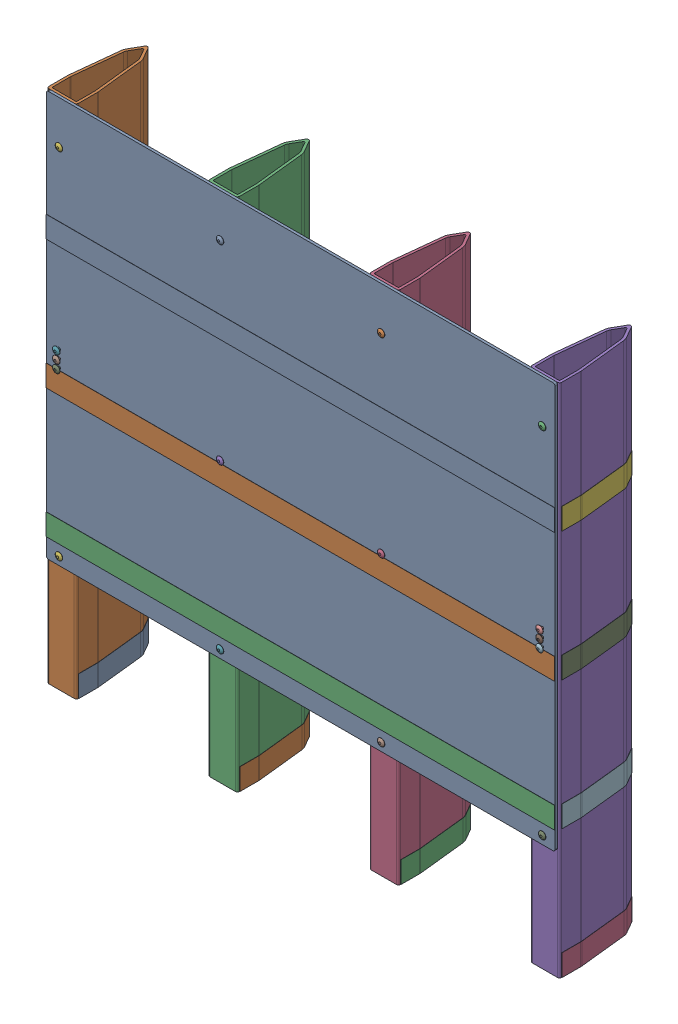
SolidWorks assembly FIELD_RelicRecovery_Crytobox C2_Cryptobox only_2, configuration Default. Lengths in mm.
Overall size (606.93 609.6 109.77).
40 component instances, 5 part files, 0 mates.
Components (placement in the parent):
- FIELD_RelicRecovery_Back Plate-1: FIELD_RelicRecovery_Back Plate [Default] at (0 317.5 -5.54) size (601.35 479.43 3)
- FIELD_RelicRecovery_Crytobox EX Rim-Triangle-1: FIELD_RelicRecovery_Crytobox EX Rim-Triangle [Default] at (-285.75 12.7 -5.54) size (34.92 609.6 101.59)
- FIELD_RelicRecovery_Crytobox EX Rim-Triangle-2: FIELD_RelicRecovery_Crytobox EX Rim-Triangle [Default] at (-95.25 12.7 -5.54) size (34.92 609.6 101.59)
- FIELD_RelicRecovery_Crytobox EX Rim-Triangle-3: FIELD_RelicRecovery_Crytobox EX Rim-Triangle [Default] at (95.25 12.7 -5.54) size (34.92 609.6 101.59)
- FIELD_RelicRecovery_Crytobox EX Rim-Triangle-4: FIELD_RelicRecovery_Crytobox EX Rim-Triangle [Default] at (285.75 12.7 -5.54) size (34.92 609.6 101.59)
- FIELD_RelicRecovery_0125 x 0500 Rivet-1: FIELD_RelicRecovery_0125 x 0500 Rivet [Default] at (-285.75 571.5 -12.065) x (1 0 0) z (0 -1 0) size (8.64 11.27 8.64)
- FIELD_RelicRecovery_0125 x 0500 Rivet-2: FIELD_RelicRecovery_0125 x 0500 Rivet [Default] at (-285.75 364.7758 -8.89) x (1 0 0) z (0 -1 0) size (8.64 11.27 8.64)
- FIELD_RelicRecovery_0125 x 0500 Rivet-3: FIELD_RelicRecovery_0125 x 0500 Rivet [Default] at (-285.75 355.2507 -8.89) x (1 0 0) z (0 -1 0) size (8.64 11.27 8.64)
- FIELD_RelicRecovery_0125 x 0500 Rivet-4: FIELD_RelicRecovery_0125 x 0500 Rivet [Default] at (-285.75 345.7258 -8.89) x (1 0 0) z (0 -1 0) size (8.64 11.27 8.64)
- FIELD_RelicRecovery_0125 x 0500 Rivet-5: FIELD_RelicRecovery_0125 x 0500 Rivet [Default] at (285.75 364.7758 -8.89) x (1 0 0) z (0 -1 0) size (8.64 11.27 8.64)
- FIELD_RelicRecovery_0125 x 0500 Rivet-6: FIELD_RelicRecovery_0125 x 0500 Rivet [Default] at (285.75 355.2507 -8.89) x (1 0 0) z (0 -1 0) size (8.64 11.27 8.64)
- FIELD_RelicRecovery_0125 x 0500 Rivet-7: FIELD_RelicRecovery_0125 x 0500 Rivet [Default] at (285.75 345.7258 -8.89) x (1 0 0) z (0 -1 0) size (8.64 11.27 8.64)
- FIELD_RelicRecovery_0125 x 0500 Rivet-8: FIELD_RelicRecovery_0125 x 0500 Rivet [Default] at (-95.25 571.5 -12.065) x (1 0 0) z (0 -1 0) size (8.64 11.27 8.64)
- FIELD_RelicRecovery_0125 x 0500 Rivet-9: FIELD_RelicRecovery_0125 x 0500 Rivet [Default] at (95.25 571.5 -12.065) x (1 0 0) z (0 -1 0) size (8.64 11.27 8.64)
- FIELD_RelicRecovery_0125 x 0500 Rivet-10: FIELD_RelicRecovery_0125 x 0500 Rivet [Default] at (285.75 571.5 -12.065) x (1 0 0) z (0 -1 0) size (8.64 11.27 8.64)
- FIELD_RelicRecovery_0125 x 0500 Rivet-11: FIELD_RelicRecovery_0125 x 0500 Rivet [Default] at (95.25 345.7194 -12.065) x (1 0 0) z (0 -1 0) size (8.64 11.27 8.64)
- FIELD_RelicRecovery_0125 x 0500 Rivet-12: FIELD_RelicRecovery_0125 x 0500 Rivet [Default] at (-95.25 345.7194 -12.065) x (1 0 0) z (0 -1 0) size (8.64 11.27 8.64)
- FIELD_RelicRecovery_0125 x 0500 Rivet-13: FIELD_RelicRecovery_0125 x 0500 Rivet [Default] at (-285.75 152.4 -12.065) x (1 0 0) z (0 -1 0) size (8.64 11.27 8.64)
- FIELD_RelicRecovery_0125 x 0500 Rivet-14: FIELD_RelicRecovery_0125 x 0500 Rivet [Default] at (-95.25 152.4 -12.065) x (1 0 0) z (0 -1 0) size (8.64 11.27 8.64)
- FIELD_RelicRecovery_0125 x 0500 Rivet-15: FIELD_RelicRecovery_0125 x 0500 Rivet [Default] at (95.25 152.4 -12.065) x (1 0 0) z (0 -1 0) size (8.64 11.27 8.64)
- FIELD_RelicRecovery_0125 x 0500 Rivet-16: FIELD_RelicRecovery_0125 x 0500 Rivet [Default] at (285.75 152.4 -12.065) x (1 0 0) z (0 -1 0) size (8.64 11.27 8.64)
- FIELD_RelicRecovery_Crypto tape wrap-1: FIELD_RelicRecovery_Crypto tape wrap [Default] at (-285.75 177.8 -5.54) size (35.43 25.4 99.31)
- FIELD_RelicRecovery_Crypto tape wrap-2: FIELD_RelicRecovery_Crypto tape wrap [Default] at (-285.75 330.2 -5.54) size (35.43 25.4 99.31)
- FIELD_RelicRecovery_Crypto tape wrap-3: FIELD_RelicRecovery_Crypto tape wrap [Default] at (-285.75 482.6 -5.54) size (35.43 25.4 99.31)
- FIELD_RelicRecovery_Crypto tape back plate-1: FIELD_RelicRecovery_Crypto tape back plate [Default] at (0 482.6 -2.54) size (601.35 25.4 0.25)
- FIELD_RelicRecovery_Crypto tape back plate-2: FIELD_RelicRecovery_Crypto tape back plate [Default] at (0 330.2 -2.54) size (601.35 25.4 0.25)
- FIELD_RelicRecovery_Crypto tape back plate-3: FIELD_RelicRecovery_Crypto tape back plate [Default] at (0 177.8 -2.54) size (601.35 25.4 0.25)
- FIELD_RelicRecovery_Crypto tape wrap-4: FIELD_RelicRecovery_Crypto tape wrap [Default] at (-95.25 482.6 -5.54) size (35.43 25.4 99.31)
- FIELD_RelicRecovery_Crypto tape wrap-5: FIELD_RelicRecovery_Crypto tape wrap [Default] at (95.25 482.6 -5.54) size (35.43 25.4 99.31)
- FIELD_RelicRecovery_Crypto tape wrap-6: FIELD_RelicRecovery_Crypto tape wrap [Default] at (285.75 482.6 -5.54) size (35.43 25.4 99.31)
- FIELD_RelicRecovery_Crypto tape wrap-7: FIELD_RelicRecovery_Crypto tape wrap [Default] at (-95.25 330.2 -5.54) size (35.43 25.4 99.31)
- FIELD_RelicRecovery_Crypto tape wrap-8: FIELD_RelicRecovery_Crypto tape wrap [Default] at (95.25 330.2 -5.54) size (35.43 25.4 99.31)
- FIELD_RelicRecovery_Crypto tape wrap-9: FIELD_RelicRecovery_Crypto tape wrap [Default] at (285.75 330.2 -5.54) size (35.43 25.4 99.31)
- FIELD_RelicRecovery_Crypto tape wrap-10: FIELD_RelicRecovery_Crypto tape wrap [Default] at (-95.25 177.8 -5.54) size (35.43 25.4 99.31)
- FIELD_RelicRecovery_Crypto tape wrap-11: FIELD_RelicRecovery_Crypto tape wrap [Default] at (95.25 177.8 -5.54) size (35.43 25.4 99.31)
- FIELD_RelicRecovery_Crypto tape wrap-12: FIELD_RelicRecovery_Crypto tape wrap [Default] at (285.75 177.8 -5.54) size (35.43 25.4 99.31)
- FIELD_RelicRecovery_Crypto tape wrap-13: FIELD_RelicRecovery_Crypto tape wrap [Default] at (-285.75 25.4 -5.54) size (35.43 25.4 99.31)
- FIELD_RelicRecovery_Crypto tape wrap-14: FIELD_RelicRecovery_Crypto tape wrap [Default] at (-95.25 25.4 -5.54) size (35.43 25.4 99.31)
- FIELD_RelicRecovery_Crypto tape wrap-15: FIELD_RelicRecovery_Crypto tape wrap [Default] at (95.25 25.4 -5.54) size (35.43 25.4 99.31)
- FIELD_RelicRecovery_Crypto tape wrap-16: FIELD_RelicRecovery_Crypto tape wrap [Default] at (285.75 25.4 -5.54) size (35.43 25.4 99.31)
